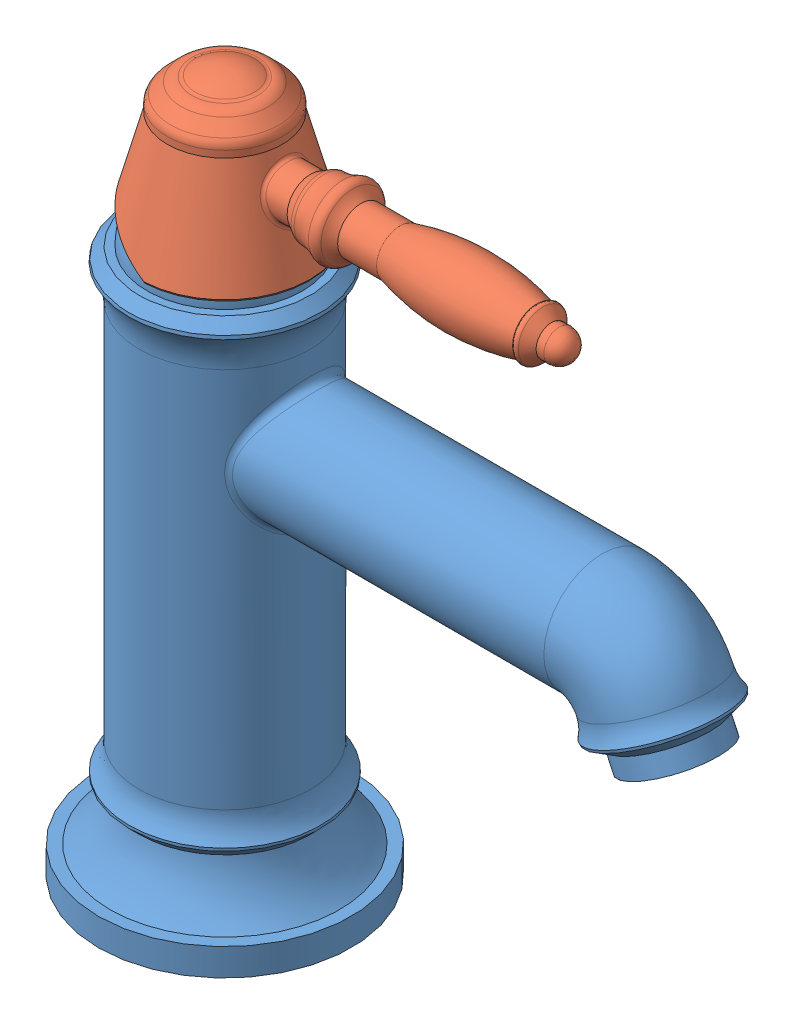
SolidWorks assembly Bathroom_faucet, configuration Default. Lengths in mm.
Overall size (159.87 180 65).
2 component instances, 2 part files, 3 mates.
Components (placement in the parent):
- base-1: base [Default] at origin size (159.87 157.32 65)
- Handle-1: Handle [Default] at (0 143 0) size (111.87 37 43.74)
Mates (geometry in assembly coordinates):
- Concentric2: concentric: sphere of base-1; sphere of Handle-1
- Parallel1: parallel anti-aligned: plane of base-1 through (0 140 0) normal (0 1 0); plane of Handle-1 through (0 143 0) normal (0 -1 0)
- Coincident2: coincident aligned: plane of base-1 through (0 0 0) normal (0 0 1); plane of Handle-1 through (0 143 0) normal (0 0 1)
